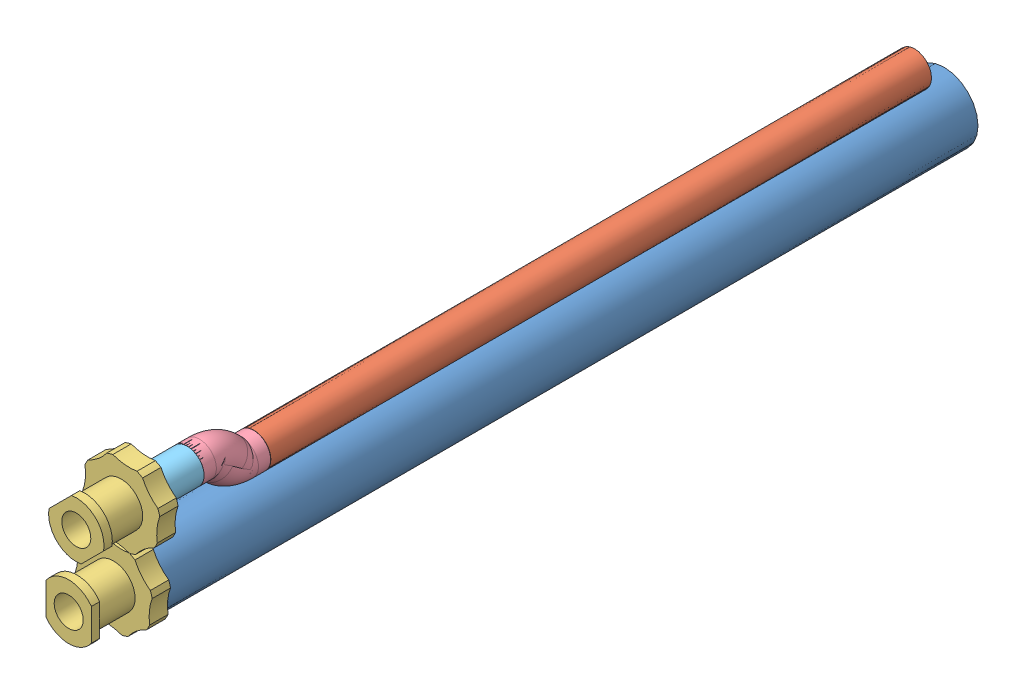
SolidWorks assembly tube assem, configuration Default. Lengths in mm.
Overall size (10.25 15.76 82.13).
7 component instances, 5 part files, 7 mates.
Components (placement in the parent):
- long tube-1: long tube [Default] x (-1 0 0) z (0 0 1) size (6.35 6.35 76.2)
- short tube-1: short tube [Default] at (0.7155 5.1856 65.4617) x (0.872865 -0.487962 0) z (0 0 -1) size (3.17 3.17 61.98)
- LUER LOCK-3: LUER LOCK [Default] at (0 0 65.6348) size (7.25 7.25 12.43)
- LUER LOCK-4: LUER LOCK [Default] at (0.7123 7.0161 65.6348) x (0.707107 -0.707107 0) z (0 0 1) size (7.25 7.25 12.43)
- 1946K240_MARINE-RATED COPPER-NICKEL PIPE FITTING-1: 1946K240_MARINE-RATED COPPER-NICKEL PIPE FITTING [1946K24] at (0.7123 10.6533 67.5596) x (-1 0 0) z (0 -0.707107 0.707107) size (3.18 5.73 4.6)
- 1946K240_MARINE-RATED COPPER-NICKEL PIPE FITTING-2: 1946K240_MARINE-RATED COPPER-NICKEL PIPE FITTING [1946K24] at (0.7155 1.5483 69.6519) x (-1 0 0) z (0 0.707107 -0.707107) size (3.18 5.73 4.6)
- tube small-1: tube small [Default] at (0.7123 7.0161 70.612) size (3.17 3.17 5.59)
Mates (geometry in assembly coordinates):
- Coincident7: coincident: point of LUER LOCK-3; point of LUER LOCK-4
- Coincident8: coincident: point of LUER LOCK-3; point of LUER LOCK-4
- Concentric14: concentric anti-aligned: circle of LUER LOCK-4; circle of 1946K240_MARINE-RATED COPPER-NICKEL PIPE FITTING-1
- Lock1: lock: unknown of 1946K240_MARINE-RATED COPPER-NICKEL PIPE FITTING-1; unknown of 1946K240_MARINE-RATED COPPER-NICKEL PIPE FITTING-2
- Concentric16: concentric aligned: circle of short tube-1; circle of 1946K240_MARINE-RATED COPPER-NICKEL PIPE FITTING-2
- Concentric17: concentric anti-aligned: circle of LUER LOCK-4; circle of tube small-1
- Coincident11: coincident anti-aligned: plane of LUER LOCK-4 through (0.7123 7.0161 76.2) normal (0 0 -1); plane of tube small-1 through (0.7123 7.0161 76.2) normal (0 0 1)
